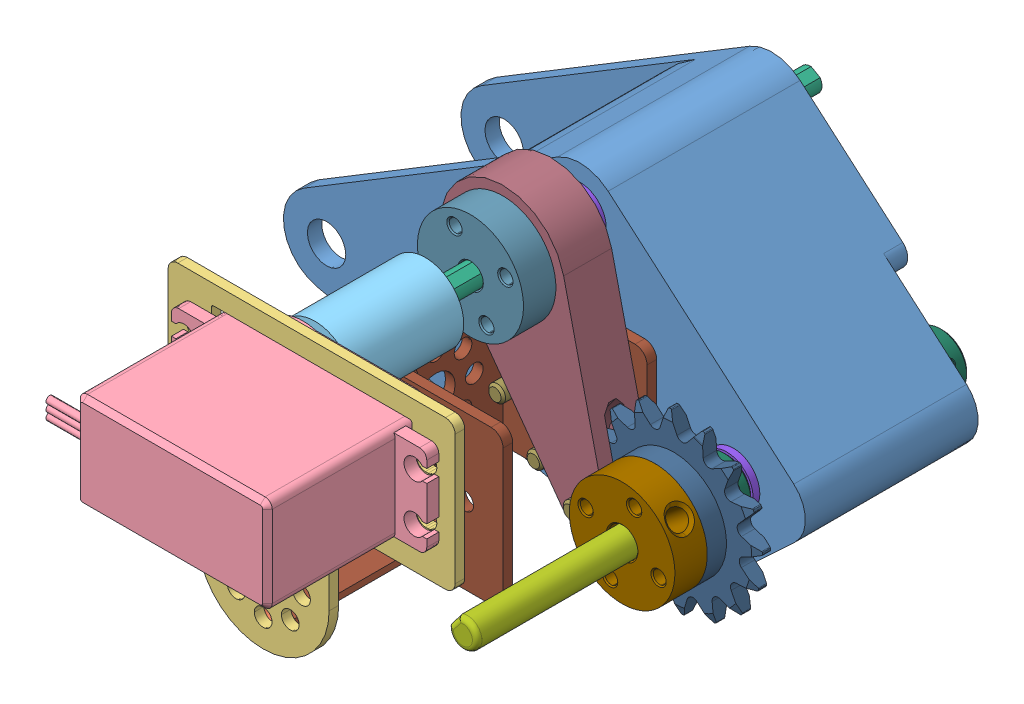
SolidWorks assembly 8699-18-205 Lander Latcher Drive Adj, configuration Default. Lengths in mm.
Overall size (116.51 74.65 143.2).
21 component instances, 15 part files, 58 mates.
Components (placement in the parent):
- 8699-18-364 Lock Adjustment Plate-1: 8699-18-364 Lock Adjustment Plate [Default] at origin size (108.78 66.42 40)
- tetrix_739107_32mm_standoff-1: tetrix_739107_32mm_standoff [Default] at (80.8213 0.0145 47.7605) size (7.16 6.2 32)
- tetrix_741789-1: tetrix_741789 [Default] at (52.7846 32 86) x (1 0 0) z (0 0 -1) size (59.8 60.75 2)
- tetrix_739197_servo-1: tetrix_739197_servo [Default] at (52.7846 32 88.5) x (0 1 0) z (-1 0 0) size (20 43.2 56.6)
- tetrix_739278_axle_adapter-1: tetrix_739278_axle_adapter [Default] at (52.7846 32 75.2) x (0.998477 0.055163 0) z (0 0 -1) size (16 16 23)
- tetrix_739088-1: tetrix_739088 [Default] at (52.7846 32 21.9) x (-0.87123 0.490874 0) z (0 0 -1) size (4.73 4.46 100)
- tetrix_744708_6mm-2: tetrix_744708_6mm [Default] at (92.5192 -58.7572 -38.7204) x (0.607985 0.793949 0) z (0 0 1) size (6 5.5 100)
- tetrix_739091-1: tetrix_739091 [Default] at (52.7846 32 -21.4) x (1 0 0) z (0 -1 0) size (11 12.4 11)
- tetrix_739091-2: tetrix_739091 [Default] at (84.7846 0 21.4) x (-0.82449 0.565877 0) z (-0.565877 -0.82449 0) size (11 12.4 11)
- tetrix_739091-3: tetrix_739091 [Default] at (84.7846 0 -17.4) x (-0.539749 -0.841826 0) z (-0.841826 0.539749 0) size (11 12.4 11)
- tetrix_739079_collar-1: tetrix_739079_collar [Default] at (84.7846 0 36.45) x (0.312774 0.949828 0) z (0 0 -1) size (22 22 9.5)
- tetrix_739165-1: tetrix_739165 [Default] at (84.7846 0 32.45) x (-0.312774 -0.949828 0) z (0 0 1) size (36 36 6.8)
- tetrix_739065-2: tetrix_739065 [Default] at (36.7846 0 36) x (0 0 1) z (0 1 0) size (32 32 32)
- tetrix_739091-4: tetrix_739091 [Default] at (52.7846 32 21.4) x (-0.923728 -0.383049 0) z (0.383049 -0.923728 0) size (11 12.4 11)
- tetrix_739097-1: tetrix_739097 [Default] at (44.7846 0 17) x (0.933008 0.359855 0) z (-0.359855 0.933008 0) size (5.74 16.21 5.74)
- tetrix_739097-2: tetrix_739097 [Default] at (52.7846 -8 17) x (0.058002 0.998316 0) z (-0.998316 0.058002 0) size (5.74 16.21 5.74)
- 8699-18-366 Lock-1: 8699-18-366 Lock [Default] at (52.7846 32 31.05) x (0.909547 0.415601 0) z (0 0 1) size (26 57.92 10)
- tetrix_739097-3: tetrix_739097 [Default] at (69.3764 -4.3113 26.05) x (-0.975108 0.22173 0) z (-0.22173 -0.975108 0) size (5.74 16.21 5.74)
- tetrix_739172_collar-1: tetrix_739172_collar [Default] at (52.7846 32 36.05) x (-0.909547 -0.415601 0) z (0 0 -1) size (22.1 22.1 9.5)
- tetrix_739092_collar-1: tetrix_739092_collar [Default] at (84.7846 0 -20.5) x (0.871034 0.491223 0) z (0 0 1) size (11 11 6.2)
- tetrix_739092_collar-2: tetrix_739092_collar [Default] at (84.7846 0 24.5) x (0.871034 0.491223 0) z (0 0 1) size (11 11 6.2)
Mates (geometry in assembly coordinates):
- Coincident1: coordinate: point of 8699-18-364 Lock Adjustment Plate-1; point of assembly
- Concentric1: concentric: cylinder of 8699-18-364 Lock Adjustment Plate-1 through (84.7846 0 20) axis (0 0 -1) radius 4; cylinder of ? through (84.7846 0 -20) axis (0 0 1) radius 4
- Concentric2: concentric: cylinder of 8699-18-364 Lock Adjustment Plate-1 through (84.7846 8 20) axis (0 0 -1) radius 2; cylinder of ? through (84.7846 8 -20) axis (0 0 1) radius 1.85
- Coincident2: coincident: plane of 8699-18-364 Lock Adjustment Plate-1 through (52.7846 32 -20) normal (0 0 -1); plane of ? through (68.7846 0 -20) normal (0 0 1)
- Concentric3: concentric: cylinder of 8699-18-364 Lock Adjustment Plate-1 through (52.7846 -8 20) axis (0 0 -1) radius 2; cylinder of tetrix_739107_32mm_standoff-1 through (52.7846 -8 52) axis (0 0 1) radius 1.35
- Coincident3: coincident: plane of 8699-18-364 Lock Adjustment Plate-1 through (52.7846 32 -20) normal (0 0 -1); plane of tetrix_739107_32mm_standoff-1 through (52.7846 -14.2 -20) normal (0 0 1)
- Concentric4: concentric: cylinder of tetrix_739107_32mm_standoff-1 through (52.7846 -8 52) axis (0 0 1) radius 1.35; cylinder of tetrix_741789-1 through (52.7846 -8 84) axis (0 0 1) radius 1.85
- Coincident4: coincident: plane of tetrix_739107_32mm_standoff-1 through (52.7846 -14.2 -52) normal (0 0 -1); plane of tetrix_741789-1
- Concentric5: concentric: cylinder of 8699-18-364 Lock Adjustment Plate-1 through (52.7846 8 20) axis (0 0 -1) radius 2; cylinder of tetrix_741789-1 through (52.7846 8 84) axis (0 0 1) radius 1.85
- Coincident5: coincident: plane of tetrix_741789-1 through (52.7846 0 86) normal (0 0 1); plane of tetrix_739197_servo-1 through (87.8846 39.875 86) normal (0 0 -1)
- Concentric6: concentric: cylinder of tetrix_739197_servo-1 through (52.7846 32 71.9) axis (0 0 1) radius 3; cylinder of tetrix_739278_axle_adapter-1 through (52.7846 32 52.2) axis (0 0 1) radius 8
- Concentric7: concentric: cylinder of 8699-18-364 Lock Adjustment Plate-1 through (52.7846 32 20) axis (0 0 -1) radius 4; cylinder of tetrix_739197_servo-1 through (52.7846 32 71.9) axis (0 0 1) radius 3
- Parallel1: parallel: plane of tetrix_741789-1 through (34.9846 47 84) normal (0 1 0); plane of tetrix_739197_servo-1 through (82.7846 42 81.1) normal (0 1 0)
- Coincident7: coincident: plane of tetrix_739197_servo-1 through (52.7846 32 75.2) normal (0 0 -1); plane of tetrix_739278_axle_adapter-1 through (52.7846 32 75.2) normal (0 0 1)
- Concentric8: concentric: cylinder of 8699-18-364 Lock Adjustment Plate-1 through (52.7846 32 20) axis (0 0 -1) radius 4; cylinder of tetrix_739091-1 through (52.7846 32 -21.4) axis (0 0 1) radius 3.925
- Coincident8: coincident: plane of 8699-18-364 Lock Adjustment Plate-1 through (52.7846 32 -20) normal (0 0 -1); plane of tetrix_739091-1 through (56.7096 32 -20) normal (0 0 1)
- Concentric9: concentric: cylinder of tetrix_739088-1 through (52.7846 32 71.9) axis (0 0 -1) radius 2.365; cylinder of tetrix_739091-1 through (52.7846 32 -21.4) axis (0 0 1) radius 2.4
- Coincident9: coincident: plane of tetrix_739197_servo-1 through (52.7846 32 71.9) normal (0 0 -1); plane of tetrix_739088-1 through (52.7846 32 71.9) normal (0 0 1)
- Concentric10: concentric: cylinder of 8699-18-364 Lock Adjustment Plate-1 through (84.7846 0 20) axis (0 0 -1) radius 4; cylinder of tetrix_744708_6mm-2 through (84.7846 0 -23.6) axis (0 0 1) radius 3
- Concentric11: concentric: cylinder of 8699-18-364 Lock Adjustment Plate-1 through (84.7846 0 20) axis (0 0 -1) radius 4; cylinder of tetrix_739091-2 through (84.7846 0 21.4) axis (0 0 -1) radius 3.925
- Coincident11: coincident: plane of 8699-18-364 Lock Adjustment Plate-1 through (52.7846 32 20) normal (0 0 1); plane of tetrix_739091-2 through (81.5485 2.2211 20) normal (0 0 -1)
- Concentric12: concentric: cylinder of tetrix_744708_6mm-2 through (84.7846 0 -23.6) axis (0 0 1) radius 3; cylinder of tetrix_739091-3 through (84.7846 0 -17.4) axis (0 0 1) radius 3.925
- Coincident12: coincident: plane of ? through (68.7846 0 -52) normal (0 0 -1); plane of tetrix_739091-3 through (81.4937 -2.1391 -52) normal (0 0 1)
- Concentric13: concentric: cylinder of tetrix_744708_6mm-2 through (84.7846 0 -23.6) axis (0 0 1) radius 3; cylinder of tetrix_739079_collar-1 through (84.7846 0 33.7) axis (0 0 1) radius 3.05
- Concentric14: concentric: cylinder of tetrix_744708_6mm-2 through (84.7846 0 -23.6) axis (0 0 1) radius 3; cylinder of tetrix_739165-1 through (84.7846 0 36.45) axis (0 0 1) radius 4
- Coincident13: coincident: plane of tetrix_739079_collar-1; plane of tetrix_739165-1 through (84.7846 0 29.65) normal (0 0 -1)
- Concentric15: concentric: cylinder of tetrix_739079_collar-1 through (87.2868 7.5986 43.2) axis (0 0 1) radius 1.3525; cylinder of tetrix_739165-1 through (87.2868 7.5986 36.45) axis (0 0 1) radius 1.8
- Coincident14: coincident: plane of tetrix_739091-2 through (80.2499 3.1123 4.575) normal (0 0 1); plane of tetrix_739079_collar-1
- Distance1: distance = 15.45 mm: plane of tetrix_739165-1 through (84.7846 0 -4.55) normal (0 0 1); plane of ? through (68.7846 0 -20) normal (0 0 1)
- Coincident15: coincident: plane of 8699-18-364 Lock Adjustment Plate-1 through (84.7846 0 -16) normal (0 0 -1); plane of tetrix_739091-3 through (82.6661 -3.3042 -16) normal (0 0 1)
- Concentric16: concentric: cylinder of 8699-18-364 Lock Adjustment Plate-1 through (52.7846 -8 20) axis (0 0 -1) radius 2; cylinder of tetrix_739065-2 through (52.7846 -8 20) axis (0 0 -1) radius 1.85
- Concentric17: concentric: cylinder of 8699-18-364 Lock Adjustment Plate-1 through (60.7846 0 20) axis (0 0 -1) radius 2; cylinder of tetrix_739065-2 through (60.7846 0 20) axis (0 0 -1) radius 1.85
- Coincident16: coincident: plane of 8699-18-364 Lock Adjustment Plate-1 through (52.7846 32 20) normal (0 0 1); plane of tetrix_739065-2 through (36.7846 0 20) normal (0 0 -1)
- Coincident17: coincident: plane of tetrix_739107_32mm_standoff-1 through (52.7846 -14.2 52) normal (0 0 -1); plane of tetrix_739065-2 through (36.7846 0 52) normal (0 0 1)
- Coincident19: coincident: plane of tetrix_739107_32mm_standoff-1 through (52.7846 -14.2 84) normal (0 0 1); plane of tetrix_741789-1 through (52.7846 0 84) normal (0 0 -1)
- Concentric19: concentric: cylinder of 8699-18-364 Lock Adjustment Plate-1 through (52.7846 32 20) axis (0 0 -1) radius 4; cylinder of tetrix_739091-4 through (52.7846 32 21.4) axis (0 0 -1) radius 3.925
- Coincident20: coincident: plane of 8699-18-364 Lock Adjustment Plate-1 through (52.7846 32 20) normal (0 0 1); plane of tetrix_739091-4 through (49.159 30.4965 20) normal (0 0 -1)
- Concentric20: concentric: cylinder of tetrix_739278_axle_adapter-1 through (52.7846 32 52.2) axis (0 0 1) radius 2.375; cylinder of tetrix_739088-1 through (52.7846 32 71.9) axis (0 0 -1) radius 2.365
- Concentric21: concentric: cylinder of tetrix_739097-2 through (52.7846 -8 29.7) axis (0 0 -1) radius 1.7526; cylinder of tetrix_739065-2 through (52.7846 -8 20) axis (0 0 -1) radius 1.85
- Concentric22: concentric: cylinder of tetrix_739065-2 through (44.7846 0 20) axis (0 0 -1) radius 1.85; cylinder of tetrix_739097-1 through (44.7846 0 29.7) axis (0 0 -1) radius 1.7526
- Coincident21: coincident: plane of 8699-18-364 Lock Adjustment Plate-1 through (52.7846 32 17) normal (0 0 -1); plane of tetrix_739097-1 through (44.7846 0 17) normal (0 0 1)
- Coincident22: coincident: plane of 8699-18-364 Lock Adjustment Plate-1 through (52.7846 32 17) normal (0 0 -1); plane of tetrix_739097-2 through (52.7846 -8 17) normal (0 0 1)
- Distance2: distance = 9.65 mm: plane of 8699-18-364 Lock Adjustment Plate-1 through (52.7846 32 20) normal (0 0 1); plane of tetrix_739165-1 through (84.7846 0 29.65) normal (0 0 -1)
- Concentric23: concentric: cylinder of tetrix_739088-1 through (52.7846 32 71.9) axis (0 0 -1) radius 2.365; cylinder of 8699-18-366 Lock-1 through (52.7846 32 36.05) axis (0 0 -1) radius 4
- Width1: width: plane of 8699-18-366 Lock-1 through (69.3764 -4.3113 36.05) normal (0 0 1); plane of 8699-18-366 Lock-1 through (69.3764 -4.3113 26.05) normal (0 0 -1); plane of tetrix_739165-1 through (84.7846 0 29.65) normal (0 0 -1); plane of tetrix_739165-1 through (84.7846 0 32.45) normal (0 0 1)
- Concentric25: concentric: cylinder of 8699-18-366 Lock-1 through (69.3764 -4.3113 36.05) axis (0 0 -1) radius 1.395; cylinder of tetrix_739097-3 through (69.3764 -4.3113 38.75) axis (0 0 -1) radius 1.7526
- Coincident24: coincident: plane of 8699-18-366 Lock-1 through (69.3764 -4.3113 26.05) normal (0 0 -1); plane of tetrix_739097-3 through (69.3764 -4.3113 26.05) normal (0 0 1)
- Tangent2: tangent: cylinder of tetrix_739097-3 through (69.3764 -4.3113 38.75) axis (0 0 -1) radius 1.7526; plane of tetrix_739165-1 through (68.5814 -7.8394 29.65) normal (-0.746815 0.665032 0)
- Tangent3: tangent: cylinder of tetrix_739165-1 through (84.7846 0 32.45) axis (0 0 1) radius 11; cylinder of 8699-18-366 Lock-1 through (69.3764 -4.3113 36.05) axis (0 0 -1) radius 5
- Concentric29: concentric: cylinder of 8699-18-366 Lock-1 through (52.7846 32 36.05) axis (0 0 -1) radius 4; cylinder of tetrix_739172_collar-1 through (52.7846 32 36.05) axis (0 0 -1) radius 4
- Concentric30: concentric: cylinder of 8699-18-366 Lock-1 through (49.4598 39.2764 36.05) axis (0 0 -1) radius 2; cylinder of tetrix_739172_collar-1 through (49.4598 39.2764 42.8) axis (0 0 1) radius 1.3525
- Coincident25: coincident: plane of 8699-18-366 Lock-1 through (69.3764 -4.3113 36.05) normal (0 0 1); plane of tetrix_739172_collar-1 through (52.7846 32 36.05) normal (0 0 -1)
- Concentric31: concentric: cylinder of tetrix_744708_6mm-2 through (84.7846 0 -23.6) axis (0 0 1) radius 3; cylinder of tetrix_739092_collar-1 through (84.7846 0 -17.4) axis (0 0 1) radius 2.425
- Coincident26: coincident: plane of tetrix_739091-3 through (81.816 -4.63 -17.4) normal (0 0 -1); plane of tetrix_739092_collar-1 through (84.7846 0 -17.4) normal (0 0 1)
- Coincident27: coincident: plane of tetrix_744708_6mm-2 through (84.7846 0 -23.6) normal (0 0 -1); plane of tetrix_739092_collar-1 through (89.5753 2.7017 -23.6) normal (0 0 -1)
- Coincident28: coincident: plane of tetrix_739079_collar-1 through (84.7846 0 36.45) normal (0 0 -1); plane of tetrix_739165-1 through (84.7846 0 36.45) normal (0 0 1)
- Concentric32: concentric: cylinder of tetrix_744708_6mm-2 through (84.7846 0 -23.6) axis (0 0 1) radius 3; cylinder of tetrix_739092_collar-2 through (84.7846 0 27.6) axis (0 0 1) radius 2.425
- Coincident29: coincident: plane of tetrix_739091-2 through (80.2499 3.1123 21.4) normal (0 0 1); plane of tetrix_739092_collar-2 through (89.5753 2.7017 21.4) normal (0 0 -1)
